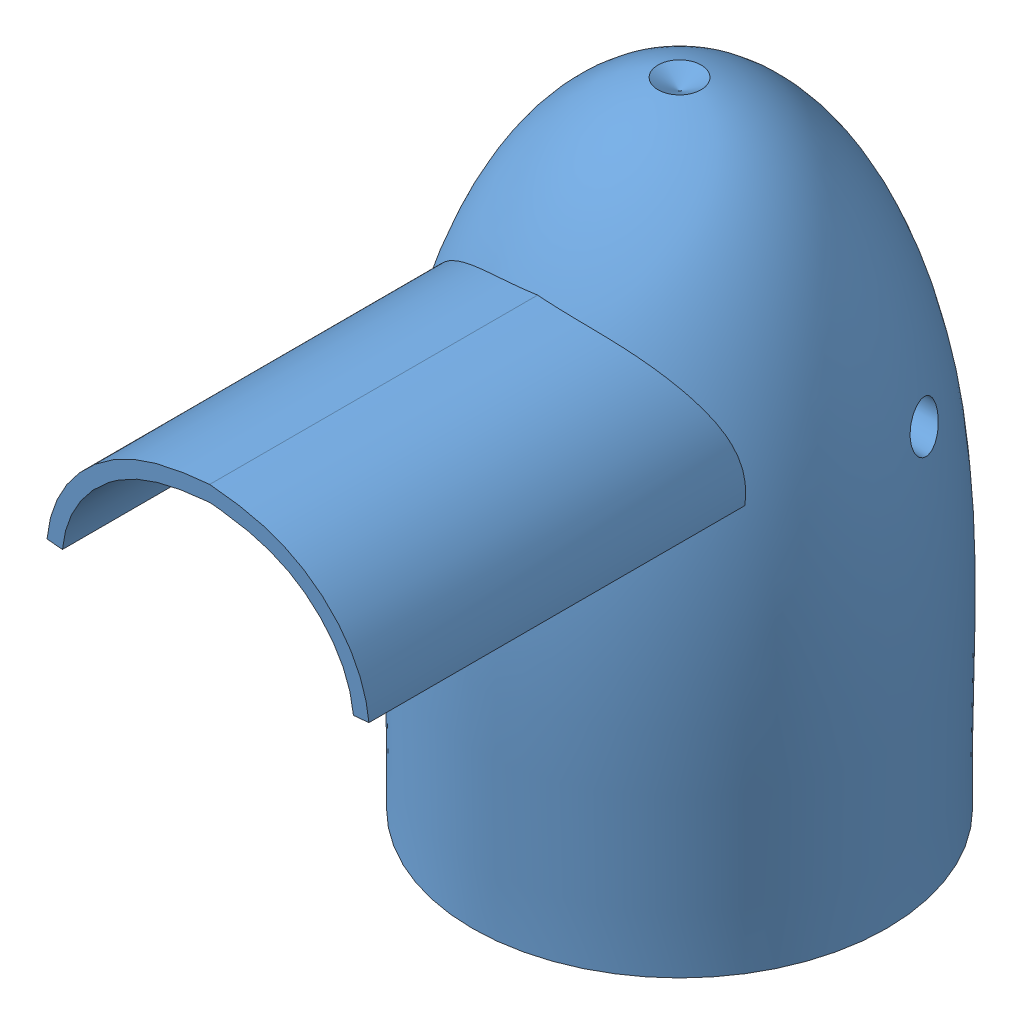
SolidWorks assembly Assem1, configuration Default. Lengths in mm.
Overall size (102.46 152.4 113.08).
2 component instances, 2 part files, 5 mates.
Components (placement in the parent):
- among_us-1: among_us [Default] x (0 0 -1) z (1 0 0) size (103.27 152.4 102.46)
- camera-1: camera [Default] at (0 95.3 -23.4507) size (38.5 38.2 90.38)
Mates (geometry in assembly coordinates):
- Coincident1: coincident anti-aligned: plane of among_us-1 through (0 0 0) normal (0 0 -1)
- Coincident2: coincident aligned: plane of among_us-1 through (0 0 0) normal (0 1 0)
- Coincident3: coincident aligned: plane of among_us-1 through (0 0 0) normal (1 0 0)
- Coincident5: coincident aligned: plane of camera-1 through (0 95.3 -23.4507) normal (1 0 0)
- Concentric2: concentric aligned: cylinder of among_us-1 through (-56.3315 95.3 -15.8964) axis (1 0 0) radius 3.175; cylinder of camera-1 through (12.0364 95.3 -15.8964) axis (1 0 0) radius 3.175
